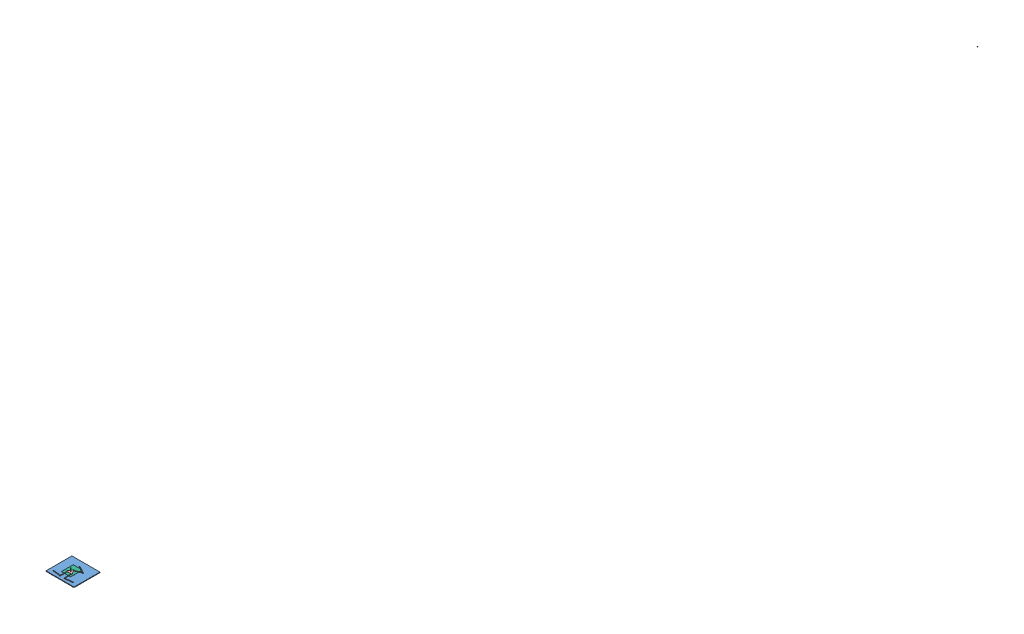
SolidWorks assembly 10_Full_3R_Assembly, configuration Default. Lengths in mm.
Overall size (660.4 172.39 21654.73).
17 component instances, 9 part files, 26 mates.
Components (placement in the parent):
- 01_Base_Plate-1: 01_Base_Plate [Default] at (-311.7855 -6.35 287.7555) size (660.4 12.7 609.6)
- 02_A_Link-1: 02_A_Link [Default] at (-219.9044 19.304 217.56) x (0.993987 0 0.109502) z (-0.109502 0 0.993987) size (200 3.17 12.7)
- 03_B_Link-1: 03_B_Link [Default] at (-26.3741 16.129 244.2974) x (-0.024664 0 -0.999696) z (0.999696 0 -0.024664) size (200 3.17 12.7)
- 02_A_Link-2: 02_A_Link [Default] at (57.889 12.954 239.132) x (0.994179 0 -0.107742) z (0.107742 0 0.994179) size (200 3.17 12.7)
- 03_B_Link-2: 03_B_Link [Default] at (51.4657 16.129 44.945) x (0.06422 0 0.997936) z (-0.997936 0 0.06422) size (200 3.17 12.7)
- 02_A_Link-3: 02_A_Link [Default] at (10.3109 16.129 -188.7321) x (0.877693 0 0.479224) z (0.479224 0 -0.877693) size (200 3.17 12.7)
- 03_B_Link-3: 03_B_Link [Default] at (1.3811 16.129 -15.1262) x (0.922231 0 -0.38664) z (0.38664 0 0.922231) size (200 3.17 12.7)
- 04_Platform-1: 04_Platform [Default] at (-59.3388 19.304 69.911) size (139.95 3.17 121.2)
- 05_Pen-1: 05_Pen [Default] at (10.6382 11.9237 29.5098) x (-0.947244 0 -0.320514) z (0.320514 0 -0.947244) size (12.7 63.5 12.7)
- 06_Paper-1: 06_Paper [Default] at (-114.9356 6.35 122.6553) size (215.9 0.25 279.4)
- 08_Roller-1: 08_Roller [Default] at (-23.9347 12.954 -21357.9807) x (0.394577 0.918848 0.005262) z (-0.696838 0.295498 0.653527) size (12.7 12.7 12.7)
- 08_Roller-2: 08_Roller [Default] at (3.5455 12.954 -29.3117) x (-0.569176 0.087987 0.817495) z (-0.816507 -0.177443 -0.54939) size (12.7 12.7 12.7)
- 08_Roller-3: 08_Roller [Default] at (13.0255 12.954 45.6316) x (-0.462433 -0.836577 0.293758) z (-0.799441 0.536688 0.269926) size (12.7 12.7 12.7)
- 07_Motor-1: 07_Motor [Default] at (243.4145 -71.5654 212.6388) x (0 1 0) z (-0.820501 0 0.571645) size (84.52 34 34)
- 07_Motor-2: 07_Motor [Default] at (-206.5855 -65.2154 212.6388) x (0 1 0) z (-0.464436 0 -0.885607) size (84.52 34 34)
- 07_Motor-3: 07_Motor [Default] at (18.4145 -71.5654 -177.0726) x (0 1 0) z (0.920755 0 -0.390141) size (84.52 34 34)
- 09_Solenoid-1: 09_Solenoid [Default] at (10.6382 100.8237 29.5098) x (0 -1 0) z (-0.032738 0 0.999464) size (25.4 12.7 12.7)
Mates (geometry in assembly coordinates):
- Coincident9: coincident aligned: circle of 02_A_Link-1; circle of 03_B_Link-1
- Coincident10: coincident aligned: circle of 03_B_Link-1; circle of 04_Platform-1
- Coincident11: coincident aligned: circle of 03_B_Link-2; circle of 04_Platform-1
- Coincident12: coincident aligned: circle of 03_B_Link-3; circle of 04_Platform-1
- Coincident13: coincident aligned: circle of 02_A_Link-2; circle of 03_B_Link-2
- Coincident15: coincident anti-aligned: circle of 02_A_Link-3; circle of 03_B_Link-3
- Concentric1: concentric aligned: circle of 01_Base_Plate-1; circle of 02_A_Link-2
- Concentric2: concentric anti-aligned: circle of 01_Base_Plate-1; circle of 02_A_Link-3
- Concentric3: concentric aligned: circle of 01_Base_Plate-1; circle of 02_A_Link-1
- Concentric4: concentric anti-aligned: circle of 04_Platform-1; circle of 05_Pen-1
- Coincident21: coincident anti-aligned: plane of 01_Base_Plate-1 through (-311.7855 6.35 287.7555) normal (0 1 0); plane of 06_Paper-1 through (-114.9356 6.35 122.6553) normal (0 -1 0)
- Distance1: distance = 196.85 mm: line of 06_Paper-1 through (-114.9356 6.604 -156.7447) axis (0 0 1); line of 01_Base_Plate-1 through (-311.7855 6.35 -321.8445) axis (0 0 1)
- Distance2: distance = 165.1 mm: line of 06_Paper-1 through (100.9644 6.604 -156.7447) axis (-1 0 0); line of 01_Base_Plate-1 through (348.6145 6.35 -321.8445) axis (-1 0 0)
- Tangent1: tangent anti-aligned: plane of 06_Paper-1 through (-114.9356 6.604 122.6553) normal (0 1 0); sphere of 08_Roller-1
- Tangent2: tangent anti-aligned: plane of 06_Paper-1 through (-114.9356 6.604 122.6553) normal (0 1 0); sphere of 08_Roller-2
- Tangent3: tangent anti-aligned: plane of 06_Paper-1 through (-114.9356 6.604 122.6553) normal (0 1 0); sphere of 08_Roller-3
- Tangent4: tangent anti-aligned: plane of 04_Platform-1 through (-59.3388 19.304 69.911) normal (0 -1 0); sphere of 08_Roller-1
- Concentric5: concentric anti-aligned: cylinder of 02_A_Link-1 through (-206.5855 19.304 212.6388) axis (0 1 0) radius 3.175; cylinder of 07_Motor-2 through (-206.5855 -83.8683 212.6388) axis (0 -1 0) radius 3
- Coincident32: coincident anti-aligned: plane of 02_A_Link-1 through (-219.9044 19.304 217.56) normal (0 -1 0); plane of 07_Motor-2 through (-205.1922 19.304 215.2957) normal (0 1 0)
- Concentric7: concentric anti-aligned: circle of 02_A_Link-2; circle of 07_Motor-1
- Coincident36: coincident anti-aligned: plane of 02_A_Link-2 through (57.889 12.954 239.132) normal (0 -1 0); plane of 07_Motor-1 through (245.876 12.954 210.9239) normal (0 1 0)
- Coincident37: coincident anti-aligned: plane of 02_A_Link-3 through (10.3109 12.954 -188.7321) normal (0 -1 0); plane of 07_Motor-3 through (15.6523 12.954 -175.9022) normal (0 1 0)
- Concentric8: concentric aligned: circle of 02_A_Link-3; circle of 07_Motor-3
- Concentric9: concentric anti-aligned: circle of 05_Pen-1; circle of 09_Solenoid-1
- Coincident38: coincident anti-aligned: plane of 05_Pen-1 through (10.6382 75.4237 29.5098) normal (0 1 0); plane of 09_Solenoid-1 through (13.8115 75.4237 29.6137) normal (0 -1 0)
- Parallel3: parallel aligned: plane of 01_Base_Plate-1 through (-311.7855 6.35 287.7555) normal (0 0 1); plane of 04_Platform-1 through (-59.3388 22.479 69.911) normal (0 0 1)
